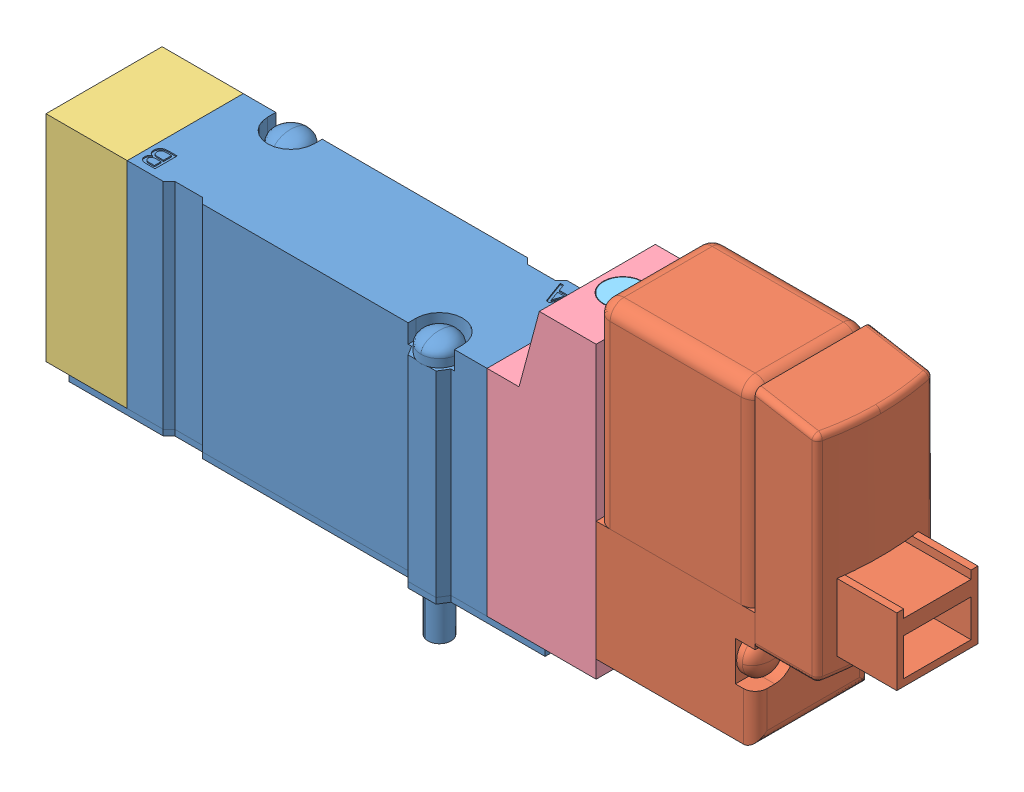
SolidWorks assembly Single Solenoid Valve 217-3233, configuration Default. Lengths in mm.
Overall size (71.8 32.6 11.8).
5 component instances, 5 part files, 0 mates.
Components (placement in the parent):
- Copy of 217-3233-001 Rev1_40^Single Solenoid Valve 217-3233-1: Copy of 217-3233-001 Rev1_40^Single Solenoid Valve 217-3233 [Default] at origin size (41 22.7 11.8) (virtual)
- Copy of 217-3233-002 Rev1_L-1^Single Solenoid Valve 217-3233-1: Copy of 217-3233-002 Rev1_L-1^Single Solenoid Valve 217-3233 [Default] at (24.9 1.5 0) x (0 -1 0) z (0 0 1) size (27 28.2 10) (virtual)
- Copy of 217-3233-003 Rev1_SingleB^Single Solenoid Valve 217-3233-1: Copy of 217-3233-003 Rev1_SingleB^Single Solenoid Valve 217-3233 [Default] at (-15.5 0 0) size (7 18.5 10) (virtual)
- Copy of 217-3233-003 Rev1_SingleA^Single Solenoid Valve 217-3233-1: Copy of 217-3233-003 Rev1_SingleA^Single Solenoid Valve 217-3233 [Default] at (15.5 0 0) x (-1 0 0) z (0 0 -1) size (9.4 25 10) (virtual)
- Copy of 217-3233-005 Rev1_P^Single Solenoid Valve 217-3233-1: Copy of 217-3233-005 Rev1_P^Single Solenoid Valve 217-3233 [Default] at (22.2 24.5 0) x (-0.965926 0 -0.258819) z (0.258819 0 -0.965926) size (3.3 0.5 3.3) (virtual)
